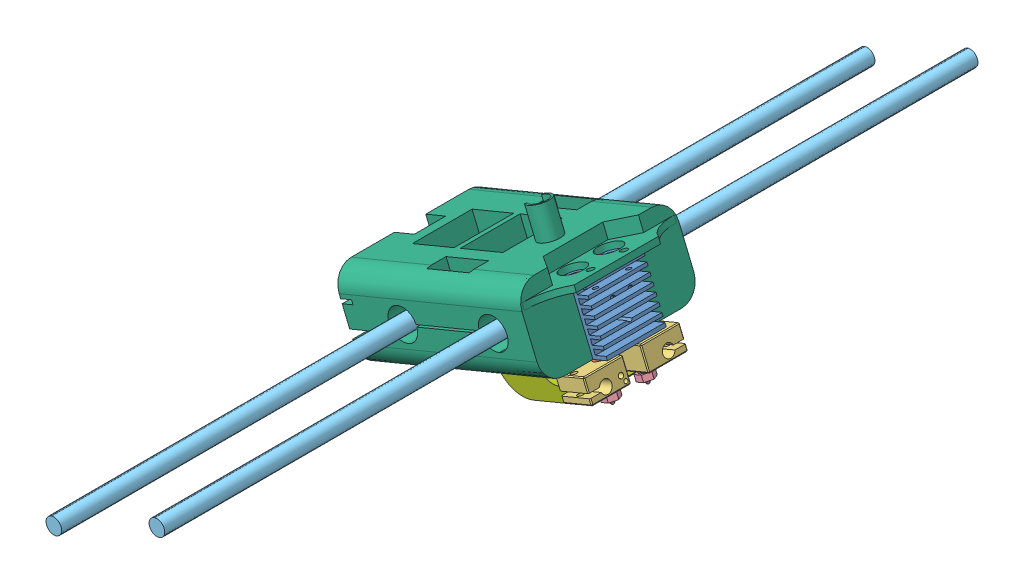
SolidWorks assembly X_assem, configuration Default. Lengths in mm.
Overall size (129.64 94 421.41).
12 component instances, 7 part files, 7 mates.
Components (placement in the parent):
- E3D chimera-1: E3D chimera [Default] at (25.7727 -18.2099 67.688) x (0 0 1) z (-0.923728 -0.383049 0) size (49 50.6 20)
  - heat sink-1: heat sink [Default] at (5.509 2.1803 24.9939) size (30 30 18)
  - heat break-1: heat break [Default] at (-3.491 -5.9197 27.9939) size (6.9 21.1 6.9)
  - heat break-2: heat break [Default] at (14.509 -5.9197 27.9939) x (0.999995 0 -0.003239) z (0.003239 0 0.999995) size (6.9 21.1 6.9)
  - heater block-1: heater block [Default] at (20.009 -11.9197 27.9939) x (-1 0 0) z (0 0 -1) size (20 11.5 16)
  - heater block-2: heater block [Default] at (-8.991 -11.9738 27.9939) size (20 11.5 16)
  - 0.4 nozzle-1: 0.4 nozzle [Default] at (14.509 -18.4197 27.9939) size (7 12.5 8.08)
  - 0.4 nozzle-2: 0.4 nozzle [Default] at (-3.491 -18.4197 27.9939) size (7 12.5 8.08)
- 8mmLinear415-1: 8mmLinear415 [Default] at (-69.5482 -33.7256 -123.984) size (8 8 415)
- 8mmLinear415-2: 8mmLinear415 [Default] at (-23.3618 -14.5731 -130.3916) size (8 8 415)
- X_carriage_v2-1: X_carriage_v2 [Default] at (-23.3618 -14.5731 112.947) x (-0.923728 -0.383049 0) z (0 0 -1) size (111 55 80)
- X_carriage_v2_blower-1: X_carriage_v2_blower [Default] at (-52.6112 -38.6733 57.697) x (0.923728 0.383049 0) z (0 0 1) size (45.05 28.23 30)
Mates (geometry in assembly coordinates):
- Concentric4: concentric anti-aligned: cylinder of 8mmLinear415-2 through (-23.3618 -14.5731 284.6084) axis (0 0 -1) radius 4; cylinder of X_carriage_v2-1 through (-23.3618 -14.5731 32.947) axis (0 0 1) radius 7.6
- Concentric5: concentric anti-aligned: cylinder of 8mmLinear415-1 through (-69.5482 -33.7256 291.016) axis (0 0 -1) radius 4; cylinder of X_carriage_v2-1 through (-69.5482 -33.7256 32.947) axis (0 0 1) radius 7.6
- Coincident5: coincident anti-aligned: plane of E3D chimera-1/heat sink-1 through (-17.955 -1.5054 88.197) normal (-0.923728 -0.383049 0); plane of X_carriage_v2-1 through (-14.1246 -10.7426 112.947) normal (0.923728 0.383049 0)
- Coincident6: coincident anti-aligned: plane of E3D chimera-1/heat sink-1 through (-1.3279 5.3895 88.197) normal (0 0 1); plane of X_carriage_v2-1 through (-21.7855 7.7319 88.197) normal (0 0 -1)
- Coincident7: coincident aligned: plane of E3D chimera-1/heat sink-1 through (1.85 -25.7698 73.197) normal (0.383049 -0.923728 0); plane of X_carriage_v2-1 through (2.7737 -25.3867 32.947) normal (0.383049 -0.923728 0)
- Coincident8: coincident anti-aligned: plane of X_carriage_v2-1 through (-25.642 -43.6655 88.197) normal (-0.923728 -0.383049 0); plane of X_carriage_v2_blower-1 through (-31.3655 -29.8631 86.697) normal (0.923728 0.383049 0)
- Coincident9: coincident anti-aligned: plane of X_carriage_v2-1 through (-47.3496 -52.6671 57.697) normal (0 0 1); plane of X_carriage_v2_blower-1 through (-33.6867 -45.1505 57.697) normal (0 0 -1)
